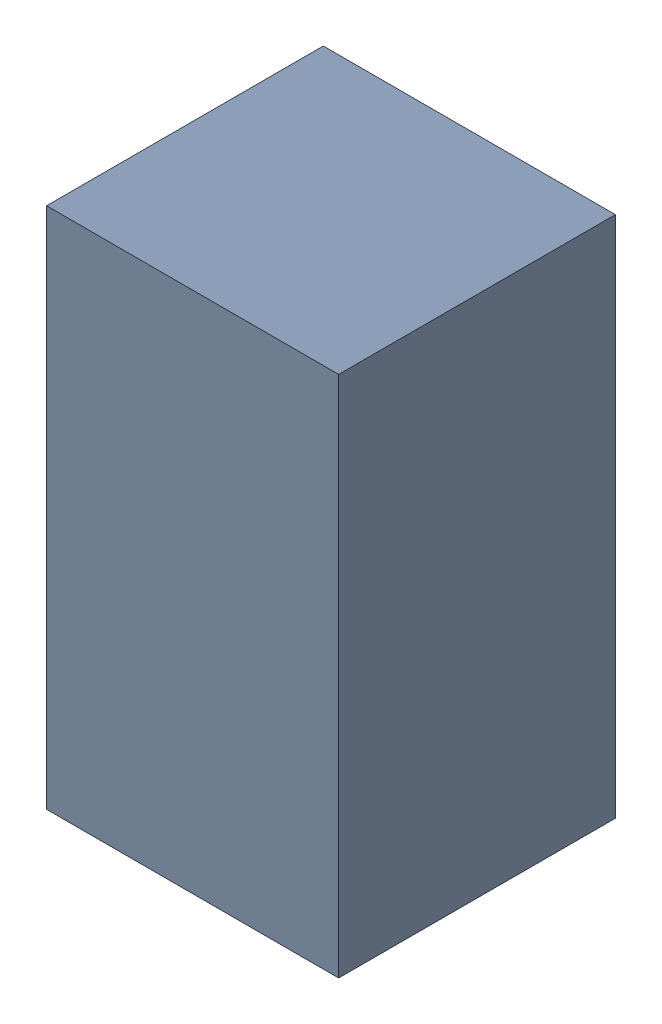
SolidWorks assembly R1_TDA1, configuration Standard. Lengths in mm.
Overall size (0.95 1.7 0.9).
2 component instances, 1 part files, 0 mates.
Components (placement in the parent):
- 885541560-1: 885541560 [Standard] at (-6.22 49.94 0) size (0.95 1.7 0.9)
  - Extruded_16-1: Extruded_16 [Standard] at origin size (0.95 1.7 0.9)
